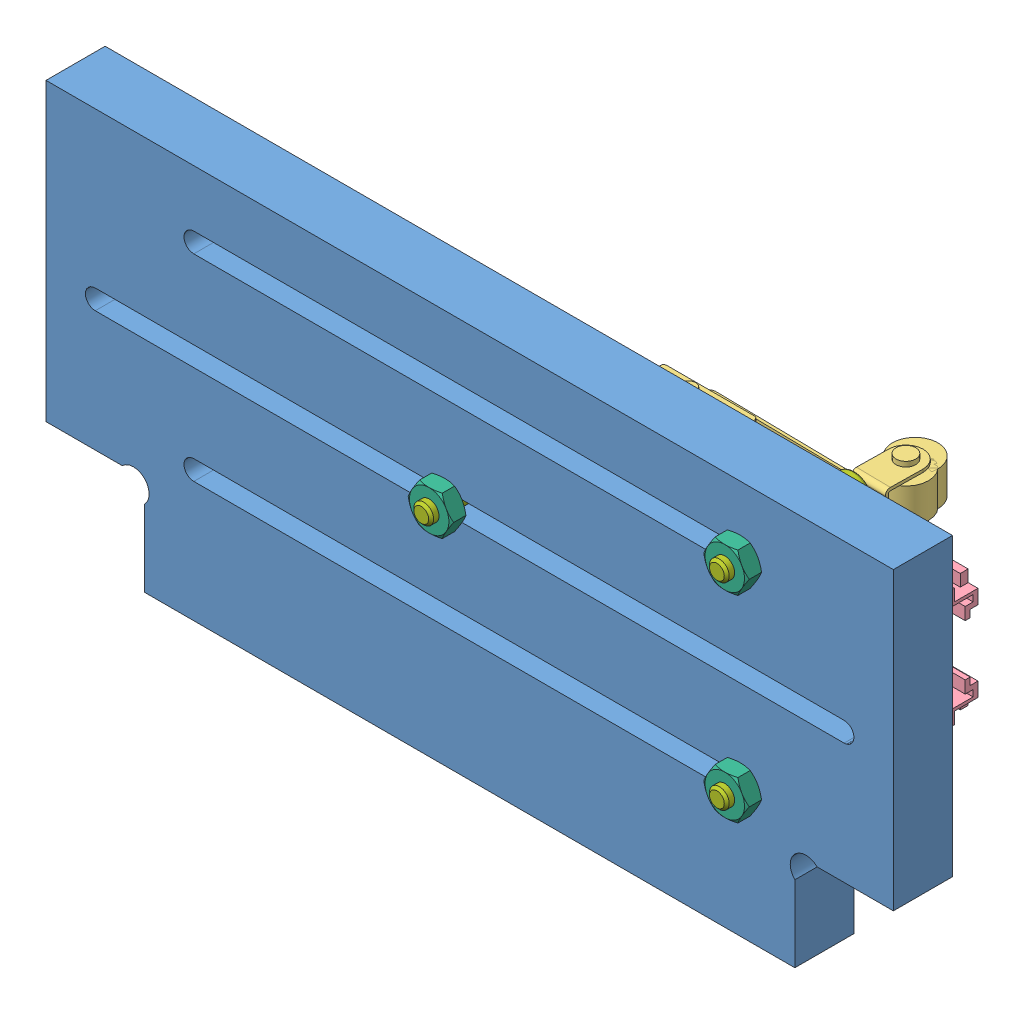
SolidWorks assembly cfc_ouvert, configuration Défaut. Lengths in mm.
Overall size (86 40 30.8).
14 component instances, 7 part files, 25 mates.
Components (placement in the parent):
- cfc-platine-1: cfc-platine [Défaut] at (140.8628 -70 0) x (0 0 1) z (0 -1 0) size (6 86 40)
- Grove microswitch v1.0-1: Grove microswitch v1.0 [Défaut] at (-27.4996 23.25 -3.344) x (-1 0 0) z (0 -1 0) size (41.8 22.4 23.6)
  - PCB grove 20x40-1: PCB grove 20x40 [Défaut] at (-1.988 -1.344 0) size (41.8 1.6 23.6)
  - microswitch 10T85-1: microswitch 10T85 [Défaut] at (9.562 0.256 0) size (22.48 22.4 6.4)
  - Connecteur Grove (coudé CMS)-1: Connecteur Grove (coudé CMS) [Défaut] at (-21.488 0.256 0) x (0 0 -1) z (0 1 0) size (12 10 5)
- entretoise-grove-1: entretoise-grove [Défaut] at (-45.5117 23.25 -2) x (1 0.000242 0) z (0 0 1) size (4 4 2)
- entretoise-grove-2: entretoise-grove [Défaut] at (-15.5117 33.25 -2) size (4 4 2)
- entretoise-grove-3: entretoise-grove [Défaut] at (-15.5117 13.25 -2) size (4 4 2)
- ecrou-h-1: ecrou-h [6007 HU M2] at (-45.5117 23.25 7.6) x (0.866025 -0.5 0) z (-0.5 -0.866025 0) size (4 1.6 4.62)
- ecrou-h-2: ecrou-h [6007 HU M2] at (-15.5117 33.25 7.6) x (0.866025 0.5 0) z (0.5 -0.866025 0) size (4 1.6 4.62)
- ecrou-h-3: ecrou-h [6007 HU M2] at (-15.5117 13.25 7.6) x (-0.866025 0.5 0) z (0.5 0.866025 0) size (4 1.6 4.62)
- vis-chc-1: vis-chc [Vis CHC M2x12] at (-15.5117 33.25 -3.6) x (1 0 0) z (0 1 0) size (3.8 14 3.8)
- vis-chc-2: vis-chc [Vis CHC M2x12] at (-15.5117 13.25 -3.6) x (1 0 0) z (0 1 0) size (3.8 14 3.8)
- vis-chc-3: vis-chc [Vis CHC M2x12] at (-45.5117 23.25 -3.6) x (0.999585 0.028802 0) z (-0.028802 0.999585 0) size (3.8 14 3.8)
Mates (geometry in assembly coordinates):
- Coaxiale1: concentric anti-aligned: cylinder of Grove microswitch v1.0-1/PCB grove 20x40-1 through (-15.5117 13.25 -3.6) axis (0 0 1) radius 1.1; cylinder of entretoise-grove-3 through (-15.5117 13.25 0) axis (0 0 -1) radius 1.2
- Coïncidente4: coincident anti-aligned: plane of Grove microswitch v1.0-1/PCB grove 20x40-1 through (-25.5117 23.25 -2) normal (0 0 1); plane of entretoise-grove-3 through (-15.5117 13.25 -2) normal (0 0 -1)
- Coaxiale2: concentric anti-aligned: cylinder of Grove microswitch v1.0-1/PCB grove 20x40-1 through (-45.5117 23.25 -3.6) axis (0 0 1) radius 1.1; cylinder of entretoise-grove-1 through (-45.5117 23.25 0) axis (0 0 -1) radius 1.2
- Coïncidente5: coincident anti-aligned: plane of Grove microswitch v1.0-1/PCB grove 20x40-1 through (-25.5117 23.25 -2) normal (0 0 1); plane of entretoise-grove-1 through (-45.5117 23.25 -2) normal (0 0 -1)
- Coaxiale3: concentric anti-aligned: cylinder of Grove microswitch v1.0-1/PCB grove 20x40-1 through (-15.5117 33.25 -3.6) axis (0 0 1) radius 1.1; cylinder of entretoise-grove-2 through (-15.5117 33.25 0) axis (0 0 -1) radius 1.2
- Coïncidente6: coincident anti-aligned: plane of Grove microswitch v1.0-1/PCB grove 20x40-1 through (-25.5117 23.25 -2) normal (0 0 1); plane of entretoise-grove-2 through (-15.5117 33.25 -2) normal (0 0 -1)
- Coïncidente7: coincident anti-aligned: plane of cfc-platine-1 through (-8.8686 8.8686 0) normal (0 0 -1); plane of entretoise-grove-1 through (-45.5117 23.25 0) normal (0 0 1)
- Parallèle4: parallel aligned: plane of cfc-platine-1 through (-86 40 6) normal (-1 0 0); plane of Grove microswitch v1.0-1/PCB grove 20x40-1 through (-45.5117 23.25 -3.6) normal (-1 0 0)
- Parallèle3: parallel aligned: plane of cfc-platine-1 through (-10 0 6) normal (0 -1 0); plane of Grove microswitch v1.0-1/PCB grove 20x40-1 through (-25.5117 13.25 -3.6) normal (0 -1 0)
- Coaxiale4: concentric anti-aligned: cylinder of Grove microswitch v1.0-1/PCB grove 20x40-1 through (-15.5117 33.25 -3.6) axis (0 0 1) radius 1.1; cylinder of vis-chc-1 through (-15.5117 33.25 8.4) axis (0 0 -1) radius 1
- Coaxiale5: concentric anti-aligned: cylinder of Grove microswitch v1.0-1/PCB grove 20x40-1 through (-45.5117 23.25 -3.6) axis (0 0 1) radius 1.1; cylinder of vis-chc-3 through (-45.5117 23.25 8.4) axis (0 0 -1) radius 1
- Coaxiale6: concentric anti-aligned: cylinder of Grove microswitch v1.0-1/PCB grove 20x40-1 through (-15.5117 13.25 -3.6) axis (0 0 1) radius 1.1; cylinder of vis-chc-2 through (-15.5117 13.25 8.4) axis (0 0 -1) radius 1
- Coïncidente11: coincident anti-aligned: plane of Grove microswitch v1.0-1/PCB grove 20x40-1 through (-25.5117 23.25 -3.6) normal (0 0 -1); plane of vis-chc-3 through (-45.5117 23.25 -3.6) normal (0 0 1)
- Coïncidente12: coincident anti-aligned: plane of Grove microswitch v1.0-1/PCB grove 20x40-1 through (-25.5117 23.25 -3.6) normal (0 0 -1); plane of vis-chc-2 through (-15.5117 13.25 -3.6) normal (0 0 1)
- Coïncidente13: coincident anti-aligned: plane of Grove microswitch v1.0-1/PCB grove 20x40-1 through (-25.5117 23.25 -3.6) normal (0 0 -1); plane of vis-chc-1 through (-15.5117 33.25 -3.6) normal (0 0 1)
- Coaxiale7: concentric anti-aligned: cylinder of ecrou-h-2 through (-15.5117 33.25 6) axis (0 0 1) radius 0.7835; cylinder of vis-chc-1 through (-15.5117 33.25 8.4) axis (0 0 -1) radius 1
- Coaxiale8: concentric anti-aligned: cylinder of ecrou-h-3 through (-15.5117 13.25 6) axis (0 0 1) radius 0.7835; cylinder of vis-chc-2 through (-15.5117 13.25 8.4) axis (0 0 -1) radius 1
- Coaxiale9: concentric anti-aligned: cylinder of ecrou-h-1 through (-45.5117 23.25 6) axis (0 0 1) radius 0.7835; cylinder of vis-chc-3 through (-45.5117 23.25 8.4) axis (0 0 -1) radius 1
- Coïncidente14: coincident anti-aligned: plane of cfc-platine-1 through (-8.8686 8.8686 6) normal (0 0 1); plane of ecrou-h-2 through (-14.357 35.25 6) normal (0 0 -1)
- Coïncidente15: coincident anti-aligned: plane of cfc-platine-1 through (-8.8686 8.8686 6) normal (0 0 1); plane of ecrou-h-1 through (-43.2023 23.25 6) normal (0 0 -1)
- Coïncidente16: coincident anti-aligned: plane of cfc-platine-1 through (-8.8686 8.8686 6) normal (0 0 1); plane of ecrou-h-3 through (-17.8211 13.25 6) normal (0 0 -1)
- Parallèle5: parallel aligned: plane of cfc-platine-1 through (0 40 6) normal (0 1 0); plane of ecrou-h-2 through (-14.357 35.25 6) normal (0 1 0)
- Parallèle6: parallel aligned: plane of ecrou-h-1 through (-44.357 25.25 6) normal (0 1 0); plane of ecrou-h-2 through (-14.357 35.25 6) normal (0 1 0)
- Parallèle7: parallel aligned: plane of ecrou-h-2 through (-14.357 35.25 6) normal (0 1 0); plane of ecrou-h-3 through (-14.357 15.25 6) normal (0 1 0)
- Tangent1: tangent anti-aligned: plane of cfc-platine-1 through (-15 32.25 6) normal (0 1 0); cylinder of vis-chc-1 through (-15.5117 33.25 8.4) axis (0 0 -1) radius 1
